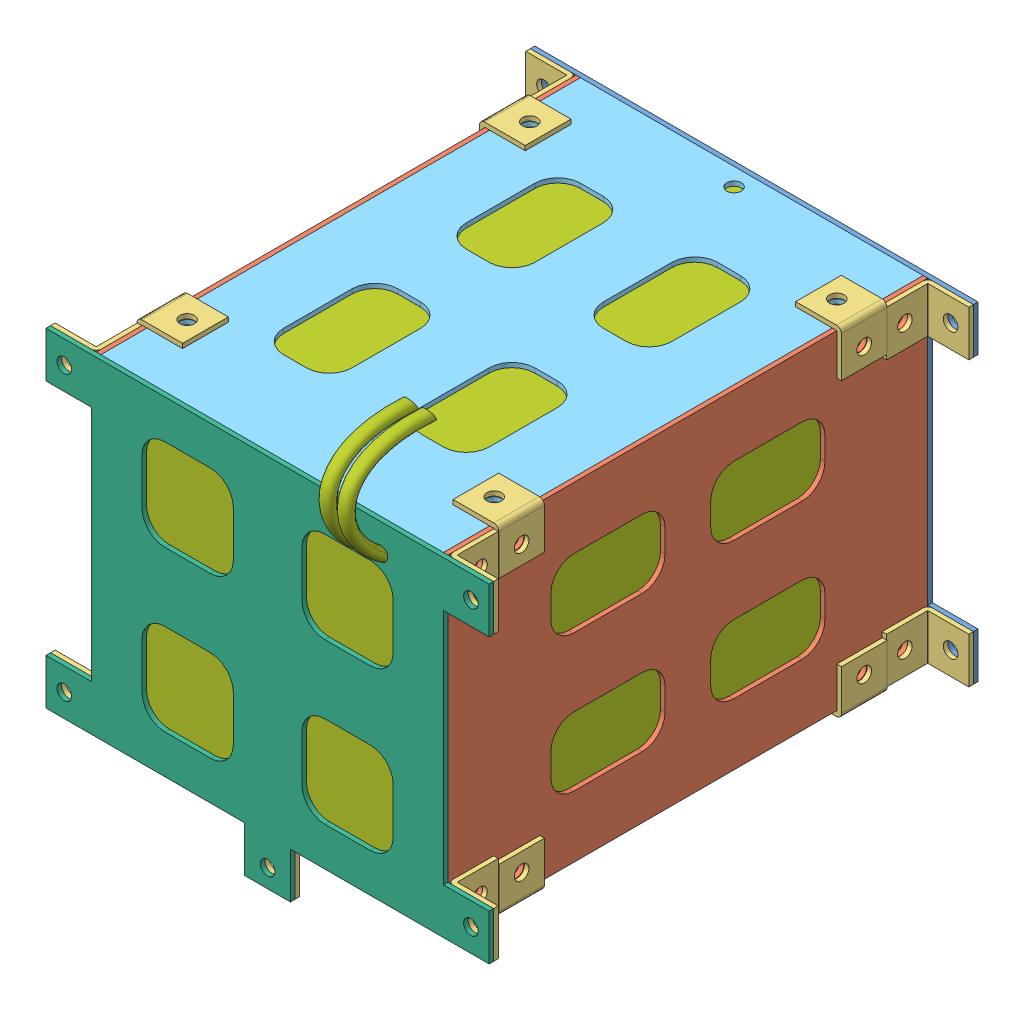
SolidWorks assembly assembly_24V, configuration Default. Lengths in mm.
Overall size (97 98.79 116.33).
25 component instances, 7 part files, 0 mates.
Components (placement in the parent):
- battery_box_24V_base-1: battery_box_24V_base [Default] at origin size (97 82 1)
- battery_box_24V_side1-1: battery_box_24V_side1 [Default] at (37.5 0 53.5) x (0 1 0) z (1 0 0) size (72 105 1)
- connector-1: connector [Default] at (43.5 31 1) x (0 -1 0) z (0 0 1) size (10 10 10)
- connector-2: connector [Default] at (-43.5 -31 106) x (0 -1 0) z (0 0 -1) size (10 10 10)
- connector-3: connector [Default] at (-43.5 31 1) x (0 1 0) z (0 0 1) size (10 10 10)
- connector-4: connector [Default] at (38.5 31 101) x (0 -1 0) z (1 0 0) size (10 10 10)
- battery_box_24V_side1-2: battery_box_24V_side1 [Default] at (-38.5 0 53.5) x (0 1 0) z (1 0 0) size (72 105 1)
- battery_box_24V_front-1: battery_box_24V_front [Default] at (0 -35 53.5) x (1 0 0) z (0 -1 0) size (75 105 1)
- connector-5: connector [Default] at (-43.5 31 106) x (0 -1 0) z (0 0 -1) size (10 10 10)
- connector-7: connector [Default] at (-39.6 32.1 16) x (0 0 1) z (1 0 0) size (10 10 10)
- connector-8: connector [Default] at (-34.6 -37.1 16) x (0 0 1) z (0 1 0) size (10 10 10)
- connector-9: connector [Default] at (0 -41 106) x (1 0 0) z (0 0 -1) size (10 10 10)
- connector-10: connector [Default] at (34.6 -37.1 16) x (0 0 -1) z (0 1 0) size (10 10 10)
- connector-11: connector [Default] at (38.5 -31 101) x (0 -1 0) z (1 0 0) size (10 10 10)
- connector-12: connector [Default] at (-43.5 -31 1) x (0 1 0) z (0 0 1) size (10 10 10)
- connector-13: connector [Default] at (0 -41 1) x (-1 0 0) z (0 0 1) size (10 10 10)
- connector-14: connector [Default] at (43.5 -31 1) x (0 -1 0) z (0 0 1) size (10 10 10)
- connector-15: connector [Default] at (39.6 32.1 16) x (0 0 -1) z (-1 0 0) size (10 10 10)
- connector-16: connector [Default] at (34.6 -37.1 91) x (0 0 -1) z (0 1 0) size (10 10 10)
- connector-17: connector [Default] at (-34.6 37.1 91) x (0 0 -1) z (0 -1 0) size (10 10 10)
- connector-18: connector [Default] at (39.6 32.1 91) x (0 0 -1) z (-1 0 0) size (10 10 10)
- connector-19: connector [Default] at (-39.6 -32.1 91) x (0 0 -1) z (1 0 0) size (10 10 10)
- battery_box_24V_back-1: battery_box_24V_back [Default] at (0 35 53.5) x (1 0 0) z (0 1 0) size (75 105 1)
- battery_box_24V_top-1: battery_box_24V_top [Default] at (0 0 106) size (97 82 1)
- battery_24V-1: battery_24V [Default] at (0 0 1) x (-1 0 0) z (0 0 1) size (75 87.79 115.33)
